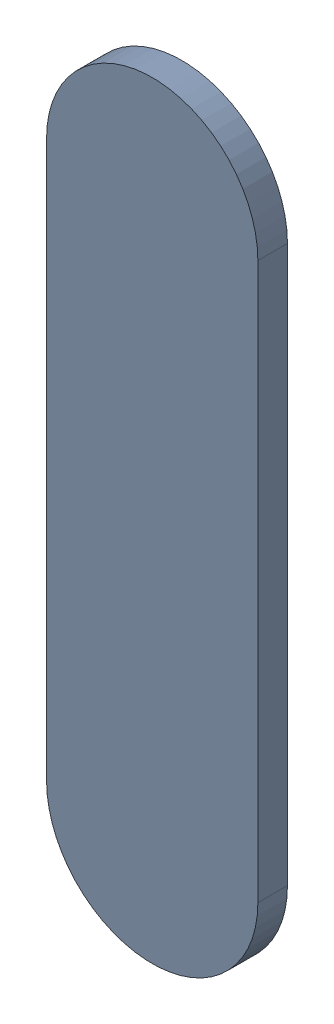
SolidWorks assembly Track (27.537mm,43.763mm)(27.537mm,44.431mm) on Top Layer, configuration Predeterminado. Lengths in mm.
Overall size (0.25 0.92 0.04).
2 component instances, 1 part files, 0 mates.
Components (placement in the parent):
- Track (27.537mm,43.763mm)(27.537mm,44.431mm) on Top Layer-1-1: Track (27.537mm,43.763mm)(27.537mm,44.431mm) on Top Layer-1 [Predeterminado] at (-68.317 -44.187 -0.0457) size (0.25 0.92 0.04)
  - Track (27.537mm,43.763mm)(27.537mm,44.431mm) on Top Layer-Part-1-1: Track (27.537mm,43.763mm)(27.537mm,44.431mm) on Top Layer-Part-1 [Predeterminado] at origin size (0.25 0.92 0.04)
